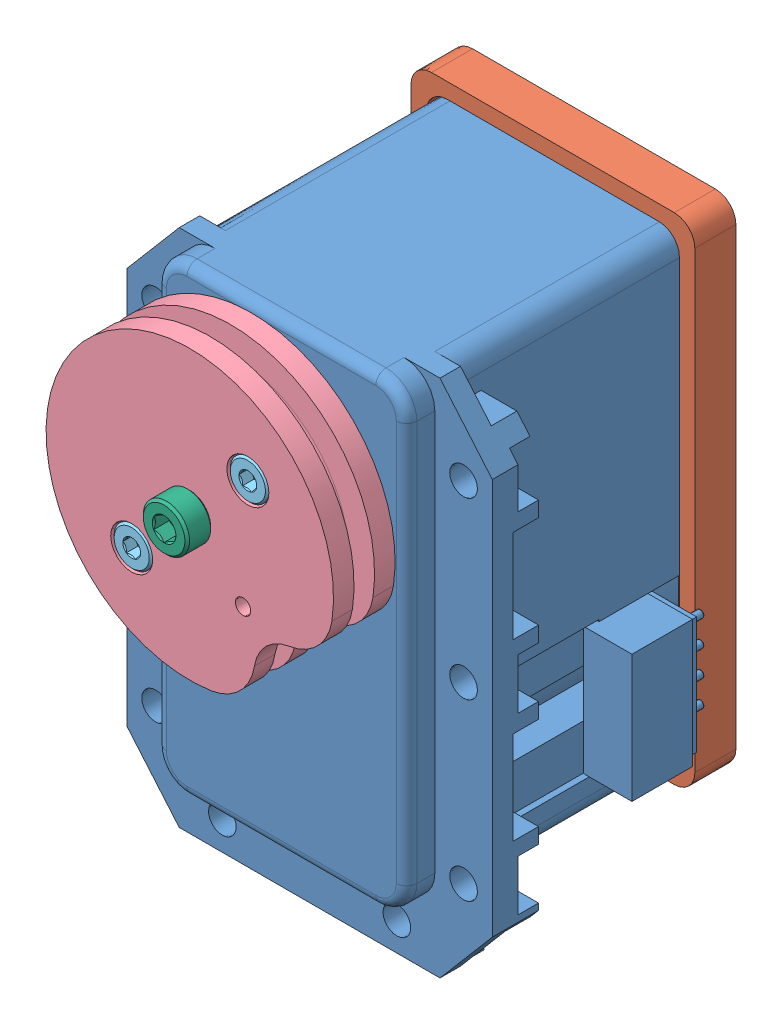
SolidWorks assembly block_actuator_pulley_o, configuration Default. Lengths in mm.
Overall size (38.36 58.4 45.54).
10 component instances, 6 part files, 20 mates.
Components (placement in the parent):
- dynamixel MX-28-exposed-1: dynamixel MX-28-exposed [Back Off] at origin size (35.6 50.6 39.77)
- d2_o-1: d2_o [Default] at (-12.375 -33.125 -8.75) x (0 1 0) z (0 0 -1) size (48.25 27.65 4)
- 91772A266 2-56 L5-4 pan-1: 91772A266 2-56 L5-4 pan [91772A266] at (-9.3 9 12.65) x (-0.205276 0.978704 0) z (0 0 -1) size (4.24 4.24 27.06)
- 91772A266 2-56 L5-4 pan-2: 91772A266 2-56 L5-4 pan [91772A266] at (9.2 9 12.65) x (-0.795891 0.60544 0) z (0 0 -1) size (4.24 4.24 27.06)
- 91772A266 2-56 L5-4 pan-3: 91772A266 2-56 L5-4 pan [91772A266] at (9.2 -30 12.65) x (-0.25415 0.967165 0) z (0 0 -1) size (4.24 4.24 27.06)
- 91772A266 2-56 L5-4 pan-4: 91772A266 2-56 L5-4 pan [91772A266] at (-9.3 -30 12.65) x (-0.098208 -0.995166 0) z (0 0 -1) size (4.24 4.24 27.06)
- b1_o-1: b1_o [Default] at (0 0 23.67) x (0.707107 -0.707107 0) z (0 0 1) size (26.25 28 6)
- 91290A012 M2 L5 socket-1: 91290A012 M2 L5 socket [91290A012] at (5.6569 5.6569 19.67) x (-0.923728 -0.383049 0) z (0 0 -1) size (3.8 3.8 7.09)
- 91290A012 M2 L5 socket-2: 91290A012 M2 L5 socket [91290A012] at (-5.6569 -5.6569 19.67) x (-0.923728 -0.383049 0) z (0 0 -1) size (3.8 3.8 7.09)
- 91292A012 M2.5 L8 socket-1: 91292A012 M2.5 L8 socket [91292A012] at (0 0 18.67) x (-0.476556 0.879144 0) z (0 0 -1) size (4.5 4.5 10.65)
Mates (geometry in assembly coordinates):
- Concentric2: concentric: cylinder of dynamixel MX-28-exposed-1 through (9.2 9 1.25) axis (0 0 -1) radius 1.15; cylinder of d2_o-1 through (9.2 9 -13.1906) axis (0 0 1) radius 1.075
- Parallel1: parallel: plane of dynamixel MX-28-exposed-1 through (12.2 12 -17.75) normal (0 1 0); plane of d2_o-1 through (-13.875 13.625 -12.75) normal (0 1 0)
- Coincident2: coincident: plane of dynamixel MX-28-exposed-1 through (-10.2 -31 -8.75) normal (0 0 -1); plane of d2_o-1 through (-12.375 -33.125 -8.75) normal (0 0 1)
- Concentric4: concentric: cylinder of d2_o-1 through (-9.3 9 -13.1906) axis (0 0 1) radius 1.075; circle of 91772A266 2-56 L5-4 pan-1
- Coincident3: coincident: plane of d2_o-1 through (-12.375 -33.125 -12.75) normal (0 0 -1); plane of 91772A266 2-56 L5-4 pan-1 through (-9.3 9 -12.75) normal (0 0 1)
- Concentric5: concentric: cylinder of d2_o-1 through (9.2 9 -13.1906) axis (0 0 1) radius 1.075; circle of 91772A266 2-56 L5-4 pan-2
- Coincident4: coincident: plane of d2_o-1 through (-12.375 -33.125 -12.75) normal (0 0 -1); plane of 91772A266 2-56 L5-4 pan-2 through (9.2 9 -12.75) normal (0 0 1)
- Concentric6: concentric: cylinder of d2_o-1 through (9.2 -30 -13.1906) axis (0 0 1) radius 1.075; circle of 91772A266 2-56 L5-4 pan-3
- Coincident5: coincident: plane of d2_o-1 through (-12.375 -33.125 -12.75) normal (0 0 -1); circle of 91772A266 2-56 L5-4 pan-3
- Concentric7: concentric: cylinder of d2_o-1 through (-9.3 -30 -13.1906) axis (0 0 1) radius 1.075; circle of 91772A266 2-56 L5-4 pan-4
- Coincident6: coincident: plane of d2_o-1 through (-12.375 -33.125 -12.75) normal (0 0 -1); plane of 91772A266 2-56 L5-4 pan-4 through (-9.3 -30 -12.75) normal (0 0 1)
- Concentric8: concentric: cylinder of dynamixel MX-28-exposed-1 through (0 0 37.8337) axis (0 0 -1) radius 4; cylinder of b1_o-1 through (0 0 26.67) axis (0 0 -1) radius 4.175
- Coincident7: coincident: plane of dynamixel MX-28-exposed-1 through (0 0 23.52) normal (0 0 1); plane of b1_o-1 through (0 0 23.52) normal (0 0 -1)
- Concentric9: concentric: circle of dynamixel MX-28-exposed-1; cylinder of b1_o-1 through (5.6569 5.6569 32.4683) axis (0 0 -1) radius 1.175
- Concentric10: concentric: cylinder of b1_o-1 through (5.6569 5.6569 26.67) axis (0 0 -1) radius 2.05; cylinder of 91290A012 M2 L5 socket-1 through (5.6569 5.6569 26.67) axis (0 0 -1) radius 1.9
- Coincident8: coincident: plane of b1_o-1 through (0 0 24.67) normal (0 0 1); plane of 91290A012 M2 L5 socket-1 through (5.6569 5.6569 24.67) normal (0 0 -1)
- Concentric11: concentric: cylinder of b1_o-1 through (-5.6569 -5.6569 26.67) axis (0 0 -1) radius 2.05; cylinder of 91290A012 M2 L5 socket-2 through (-5.6569 -5.6569 26.67) axis (0 0 -1) radius 1.9
- Coincident9: coincident: plane of b1_o-1 through (0 0 24.67) normal (0 0 1); plane of 91290A012 M2 L5 socket-2 through (-5.6569 -5.6569 24.67) normal (0 0 -1)
- Concentric12: concentric: cylinder of b1_o-1 through (0 0 8.8613) axis (0 0 1) radius 1.425; cylinder of 91292A012 M2.5 L8 socket-1 through (0 0 29.17) axis (0 0 -1) radius 2.25
- Coincident10: coincident: plane of b1_o-1 through (0 0 26.67) normal (0 0 1); plane of 91292A012 M2.5 L8 socket-1 through (0 0 26.67) normal (0 0 -1)
